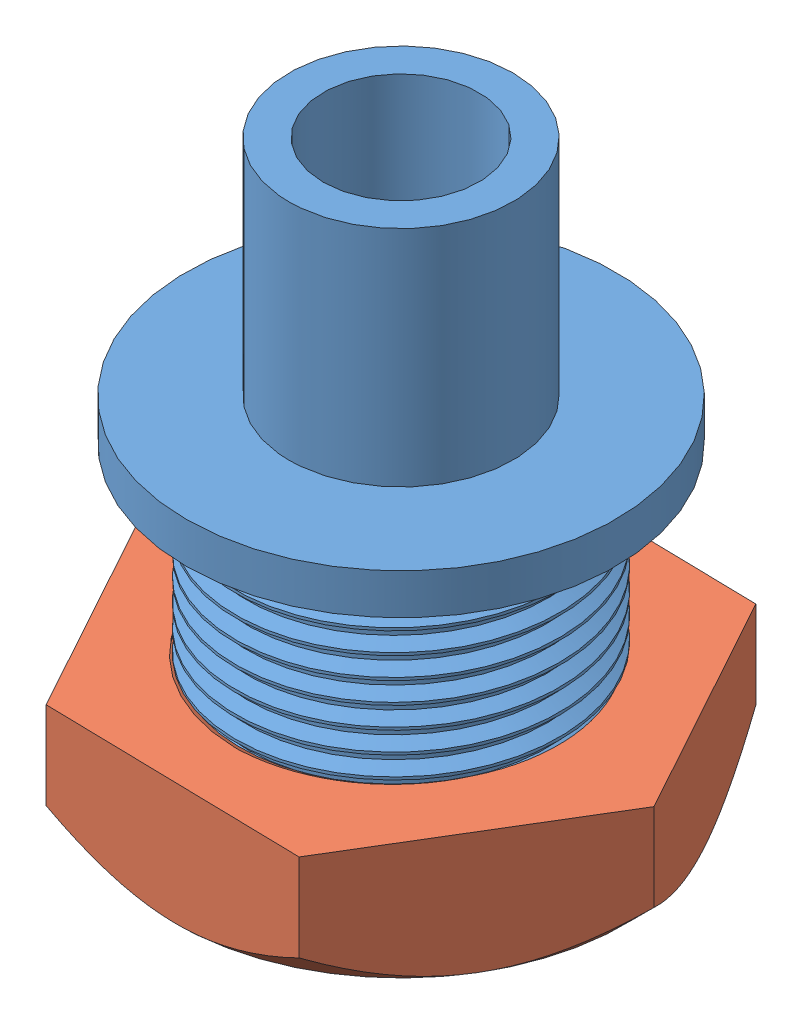
SolidWorks assembly OutputConnector, configuration Default. Lengths in mm.
Overall size (61.37 57.85 63.1).
2 component instances, 2 part files, 1 mates.
Components (placement in the parent):
- OutputConnector-Screw-1: OutputConnector-Screw [Default] at (11.0928 5.6199 34.3493) size (42.18 57.85 42.18)
- OutputConnector-Nut-1: OutputConnector-Nut [Default] at (11.0928 18.5991 34.3493) x (0.978653 0 -0.205522) z (0 -1 0) size (51.43 53.67 14.24)
Mates (geometry in assembly coordinates):
- Concentric1: concentric anti-aligned: circle of OutputConnector-Screw-1; circle of OutputConnector-Nut-1
